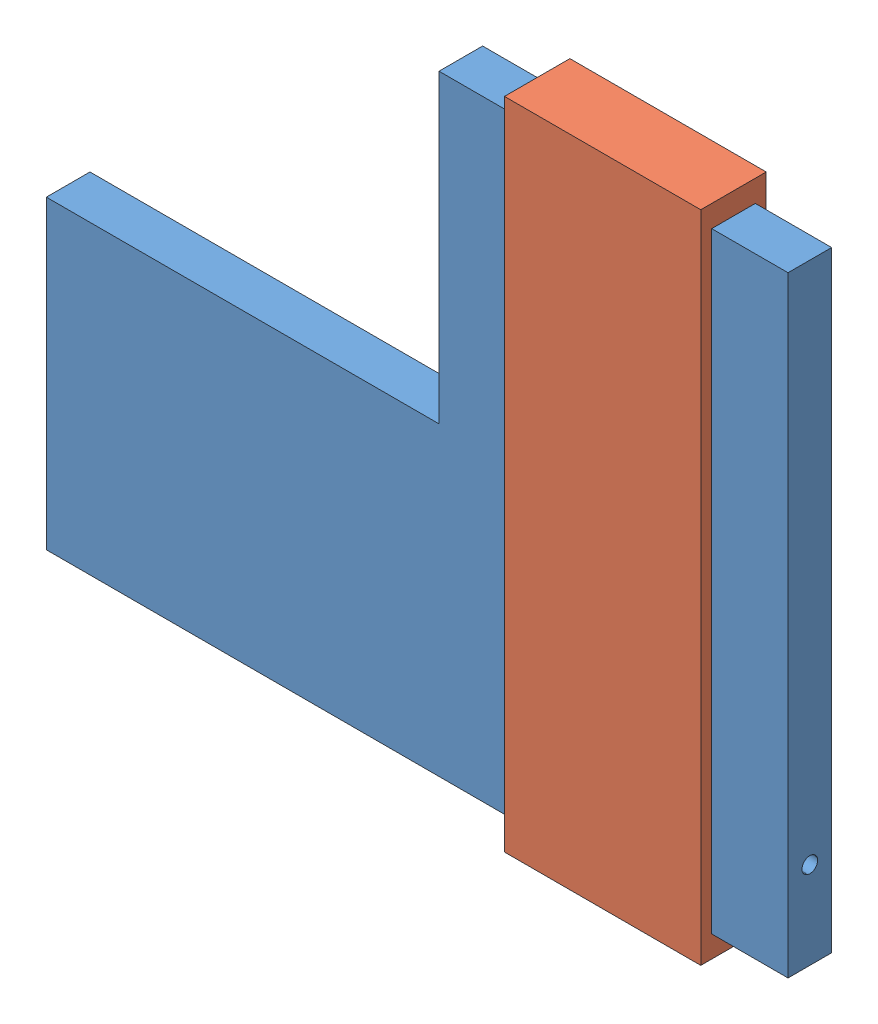
SolidWorks assembly fibre_on_frame, configuration Default. Lengths in mm.
Overall size (34 30 3).
2 component instances, 2 part files, 3 mates.
Components (placement in the parent):
- fibre_on_frame-1: fibre_on_frame [Default] at (-7.4764 -6.9944 -0.952) size (34 28.03 2.01)
- block-1: block [Default] at (-3.9764 22.0056 -1.452) x (1 0 0) z (0 -1 0) size (9 3 30)
Mates (geometry in assembly coordinates):
- Distance6: distance = 3.5 mm: plane of block-1 through (5.0236 -7.9944 -1.452) normal (1 0 0); plane of fibre_on_frame-1 through (8.5236 -6.9944 -0.552) normal (1 0 0)
- Distance7: distance = 0.5 mm: plane of block-1 through (-3.9764 -7.9944 -1.452) normal (0 0 -1); plane of fibre_on_frame-1 through (-7.4764 -6.9944 -0.952) normal (0 0 -1)
- Distance8: distance = 1 mm aligned: plane of block-1 through (-3.9764 22.0056 -1.452) normal (0 1 0); plane of fibre_on_frame-1 through (-7.4764 21.0056 1.048) normal (0 1 0)
